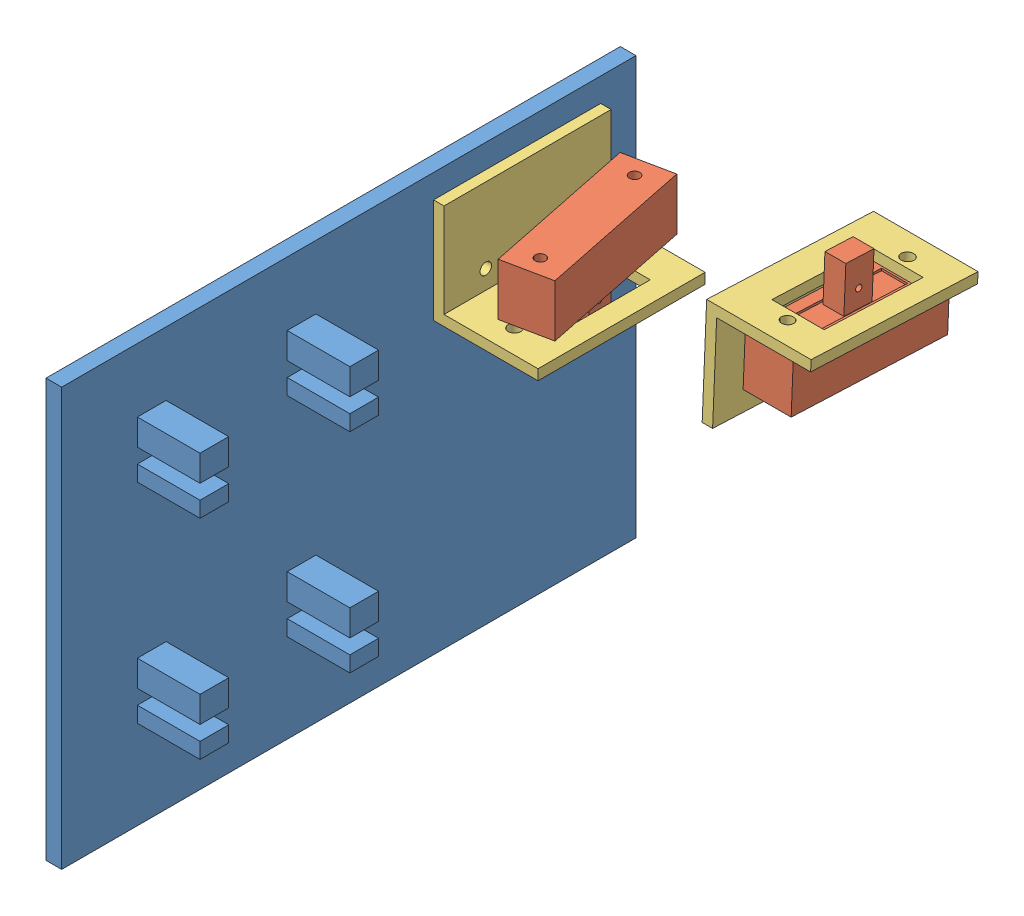
SolidWorks assembly 控制总成, configuration 默认. Lengths in mm.
Overall size (23.86 80 155.51).
5 component instances, 3 part files, 5 mates.
Components (placement in the parent):
- 电控安装层板-1: 电控安装层板 [默认] at (-10.1208 0.9995 221) size (15 80 110)
- 开关-1: 开关 [默认] at (6.2152 27.2707 203.6278) x (0 -1 0) z (0.201381 0 0.979513) size (18.2 9.2 30)
- 开关-2: 开关 [默认] at (3.8792 -13.8936 151.6796) x (0 0.999072 -0.043078) z (0 -0.043078 -0.999072) size (18.2 9.2 30)
- 开个安装架-1: 开个安装架 [默认] at (-7.1208 16.4402 203.7655) x (0 -1 0) z (0 0 1) size (20 20 32)
- 开个安装架-2: 开个安装架 [默认] at (-7.1208 -6.8958 151.478) x (0 0.999072 -0.043078) z (0 -0.043078 -0.999072) size (20 20 32)
Mates (geometry in assembly coordinates):
- 同心1: concentric aligned: cylinder of 开关-1 through (3.8792 32.2707 192.2655) axis (0 -1 0) radius 1; cylinder of 开个安装架-1 through (3.8792 46.4402 192.2655) axis (0 -1 0) radius 1.15
- 同心2: concentric aligned: cylinder of 开关-2 through (3.8792 -18.3892 163.4842) axis (0 0.999072 -0.043078) radius 1; cylinder of 开个安装架-2 through (3.8792 -36.3725 164.2597) axis (0 0.999072 -0.043078) radius 1.15
- 重合2: coincident anti-aligned: plane of 开关-2 through (8.4792 -9.5444 136.4782) normal (0 0.999072 -0.043078); plane of 开个安装架-2 through (12.8792 -9.5831 135.579) normal (0 -0.999072 0.043078)
- 重合3: coincident anti-aligned: plane of 电控安装层板-1 through (-7.1208 0.9995 221) normal (1 0 0); plane of 开个安装架-1 through (-7.1208 36.4402 219.7655) normal (-1 0 0)
- 重合4: coincident anti-aligned: plane of 电控安装层板-1 through (-7.1208 0.9995 221) normal (1 0 0); plane of 开个安装架-2 through (-7.1208 -27.5664 136.3544) normal (-1 0 0)
